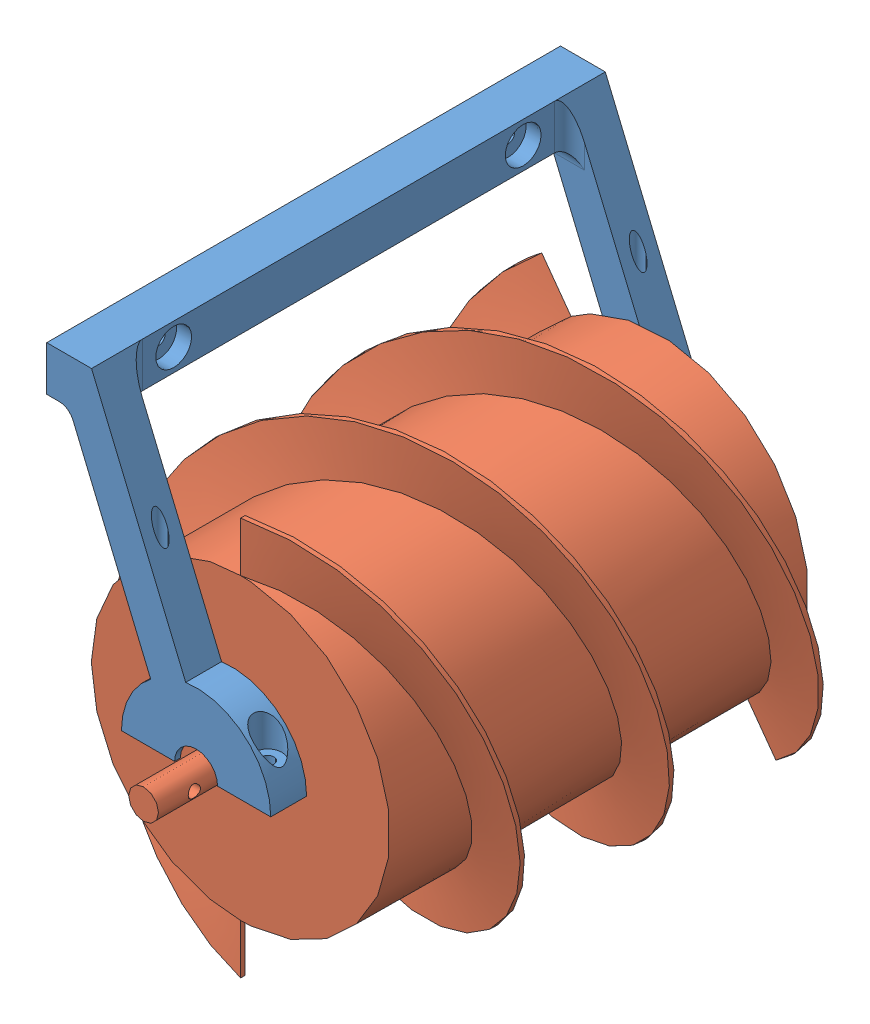
SolidWorks assembly Assem2, configuration Default. Lengths in mm.
Overall size (133.34 166.96 257.5).
2 component instances, 2 part files, 2 mates.
Components (placement in the parent):
- GSL_Feet_Left_GSL12-1: GSL_Feet_Left_GSL12 [Default] at (28.9193 160.478 126.0299) size (100 150 172)
- HGSL2_CW-1: HGSL2_CW [Default] at (71.4193 67.978 57.1099) size (133.34 133.91 257.5)
Mates (geometry in assembly coordinates):
- Distance1: distance = 5.08 mm: plane of HGSL2_CW-1 through (71.4193 67.978 57.1099) normal (0 0 -1); plane of GSL_Feet_Left_GSL12-1 through (28.9193 160.478 52.0299) normal (0 0 1)
- Concentric1: concentric: circle of GSL_Feet_Left_GSL12-1; cylinder of HGSL2_CW-1 through (71.4193 67.978 219.4499) axis (0 0 -1) radius 5
